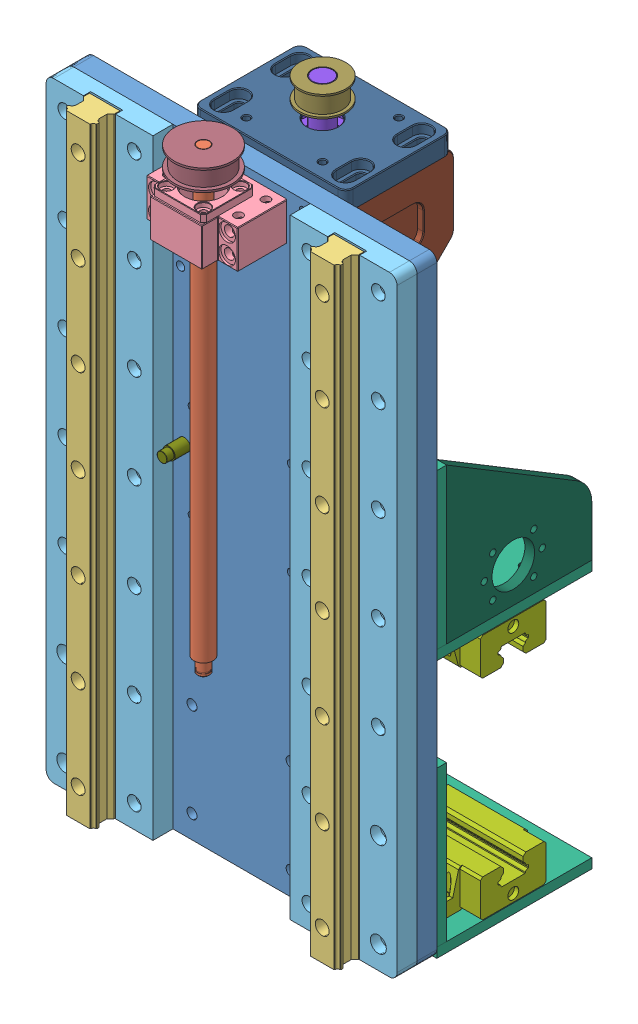
SolidWorks assembly Z Head, configuration Default. Lengths in mm.
Overall size (240 423.59 158.6).
25 component instances, 16 part files, 116 mates.
Components (placement in the parent):
- faceplate-1: faceplate [Default] at origin size (230 400 13)
- ballscrew-1: ballscrew [Z Axis] at (0 73.5865 38) x (-1 0 0) z (0 1 0) size (12.64 12.64 300)
- HGR20-1: HGR20 [400mm] at (80 0 37.15) x (1 0 0) z (0 -1 0) size (20 17.5 400)
- HGR20-2: HGR20 [400mm] at (-80 0 37.15) x (1 0 0) z (0 -1 0) size (20 17.5 400)
- BK12-1: BK12 [Default] at (0 182.35 38) x (-1 0 0) z (0 1 0) size (60 43 30.41)
- rail spacer-1: rail spacer [Right] at (80 0 13) size (70 400 13.1)
- rail spacer-2: rail spacer [Left] at (-80 0 13) x (-1 0 0) z (0 0 1) size (70 400 13.1)
- L bracket-1: L bracket [Bottom] at (0 -196.825 -50.8) size (230 107.95 101.6)
- L bracket-2: L bracket [Top] at (0 -27.905 -50.8) size (230 107.95 101.6)
- HGW20CC-1: HGW20CC [Default] at (76.37 -47.08 -50.1) size (77.26 24.9 63)
- HGW20CC-2: HGW20CC [Default] at (-76.37 -47.08 -50.1) size (77.26 24.9 63)
- HGW20CC-3: HGW20CC [Default] at (76.37 -177.65 -50.1) x (-1 0 0) z (0 0 1) size (77.26 24.9 63)
- HGW20CC-4: HGW20CC [Default] at (-76.37 -177.65 -50.1) x (-1 0 0) z (0 0 1) size (77.26 24.9 63)
- servo JMC_400W_AC_with_brake-1: servo JMC_400W_AC_with_brake [Default] at (0 74.9865 -40.1143) x (0 0 -1) z (1 0 0) size (60 164.6 60)
- nut_XY-1: nut_XY [Default] at (-103 -1.56 -50.1) x (0 0 1) z (-1 0 0) size (48 40 44)
- z motor attach-1: z motor attach [Default] at (0 186.9865 -40.1143) size (100 12.7 70)
- z motor attach supports-1: z motor attach supports [Default] at (40 146.9865 -40) size (12.7 80 80)
- z motor attach supports-2: z motor attach supports [Default] at (-40 146.9865 -40) size (12.7 80 80)
- Pulley motor-1: Pulley motor [Default] at (0 216.5865 -40.1143) x (0.999978 0 -0.006689) z (0.006689 0 0.999978) size (30.2 14 30.2)
- Pulley Z screw-1: Pulley Z screw [Default] at (0 216.5865 38) size (38 14 38)
- Z Spacer-1: Z Spacer [Default] at (-80 0 22.05) x (0 0 -1) z (1 0 0) size (1.2 400 21)
- Z Spacer-2: Z Spacer [Default] at (80 0 22.05) x (0 0 -1) z (-1 0 0) size (1.2 400 21)
- Z_nut_mount-1: Z_nut_mount [Default] at (-115 -24.73 -6.35) x (-1 0 0) z (0 0 -1) size (6.35 101.6 95.25)
- Z_nut_mount-2: Z_nut_mount [Default] at (108.65 -24.73 -6.35) x (-1 0 0) z (0 0 -1) size (6.35 101.6 95.25)
- limit_sensor-1: limit_sensor [Default] at (-37.5 22 27.6577) size (7.92 7.92 51)
Mates (geometry in assembly coordinates):
- Coincident1: coordinate: point of faceplate-1
- Distance1: distance = 12.7 mm anti-aligned: plane of servo JMC_400W_AC-1 through (30 167.3 -12.7) normal (0 0 1); plane of faceplate-1 through (0 0 0) normal (0 0 -1)
- Distance2: distance = 12.7 mm aligned: plane of servo JMC_400W_AC-1 through (0 167.3 -42.7) normal (0 1 0); plane of faceplate-1 through (115 200 13) normal (0 1 0)
- Width1: width aligned: plane of servo JMC_400W_AC-1 through (30 167.3 -72.7) normal (1 0 0); plane of faceplate-1 through (-30 167.3 -72.7) normal (-1 0 0); plane of servo JMC_400W_AC-1 through (115 200 13) normal (1 0 0); plane of faceplate-1 through (-115 200 13) normal (-1 0 0)
- Coincident5: coincident aligned: plane of faceplate-1 through (115 200 13) normal (0 1 0); plane of HGR20-1 through (70.3536 200 34.5036) normal (0 1 0)
- Coincident7: coincident aligned: plane of faceplate-1 through (115 200 13) normal (0 1 0); plane of HGR20-2 through (-89.6464 200 34.5036) normal (0 1 0)
- Coincident8: coincident anti-aligned: plane of faceplate-1 through (0 0 13) normal (0 0 1); plane of BK12-1 through (30 194.85 13) normal (0 0 -1)
- Coincident9: coincident aligned: plane of faceplate-1 through (115 200 13) normal (0 1 0); plane of BK12-1 through (0 200 38) normal (0 1 0)
- Width2: width anti-aligned: plane of BK12-1 through (-30 194.85 45.5) normal (-1 0 0); plane of faceplate-1 through (30 194.85 45.5) normal (1 0 0); plane of BK12-1 through (115 200 13) normal (1 0 0); plane of faceplate-1 through (-115 200 13) normal (-1 0 0)
- Concentric1: concentric aligned: cylinder of ballscrew-1 through (0 223.5865 38) axis (0 1 0) radius 4; cylinder of BK12-1 through (0 182.35 38) axis (0 1 0) radius 6
- Coincident10: coincident anti-aligned: plane of ballscrew-1 through (0 169.5865 42.94) normal (0 1 0); plane of BK12-1 through (6 169.5865 38) normal (0 -1 0)
- Coincident14: coincident aligned: plane of HGR20-1 through (72.35 -200 40.15) normal (0 0 1); plane of HGR20-2 through (-87.65 -200 40.15) normal (0 0 1)
- Coincident15: coincident aligned: plane of faceplate-1 through (115 200 13) normal (0 1 0); plane of rail spacer-1 through (115 200 21.45) normal (0 1 0)
- Coincident16: coincident aligned: plane of faceplate-1 through (115 200 13) normal (1 0 0); plane of rail spacer-1 through (115 200 21.45) normal (1 0 0)
- Coincident17: coincident anti-aligned: plane of faceplate-1 through (0 0 13) normal (0 0 1); plane of rail spacer-1 through (80 0 13) normal (0 0 -1)
- Coincident18: coincident anti-aligned: plane of faceplate-1 through (0 0 13) normal (0 0 1); plane of rail spacer-2 through (-80 0 13) normal (0 0 -1)
- Coincident22: coincident aligned: plane of faceplate-1 through (115 -200 13) normal (0 -1 0); plane of L bracket-1 through (115 -200 0) normal (0 -1 0)
- Coincident23: coincident anti-aligned: plane of faceplate-1 through (0 0 0) normal (0 0 -1); plane of L bracket-1 through (115 -200 0) normal (0 0 1)
- Coincident24: coincident aligned: plane of faceplate-1 through (115 200 13) normal (1 0 0); plane of L bracket-1 through (115 -196.825 -50.8) normal (1 0 0)
- Coincident28: coincident aligned: plane of HGW20CC-1 through (155.153 -40.4358 -81.6) normal (0 0 -1); plane of HGW20CC-2 through (2.413 -40.4358 -81.6) normal (0 0 -1)
- Coincident29: coincident aligned: plane of HGW20CC-1 through (155.153 -31.08 -44.745) normal (0 1 0); plane of HGW20CC-2 through (2.413 -31.08 -44.745) normal (0 1 0)
- Coincident31: coincident anti-aligned: plane of L bracket-1 through (115 -193.65 -6.35) normal (0 1 0); plane of HGW20CC-4 through (-155.153 -193.65 -44.745) normal (0 -1 0)
- Coincident32: coincident anti-aligned: plane of L bracket-1 through (115 -193.65 -6.35) normal (0 1 0); plane of HGW20CC-3 through (-2.413 -193.65 -44.745) normal (0 -1 0)
- Coincident33: coincident aligned: plane of HGW20CC-3 through (37.74 -170.22 -71.69) normal (0 0 -1); plane of HGW20CC-4 through (-115 -170.22 -71.69) normal (0 0 -1)
- Coincident34: coincident aligned: plane of L bracket-1 through (115 -196.825 -50.8) normal (1 0 0); plane of HGW20CC-3 through (115 -180.3114 -40.4536) normal (1 0 0)
- Distance6: distance = 45 mm anti-aligned: plane of HGW20CC-3 through (37.74 -173.485 -56.6) normal (0 0 1); plane of L bracket-1 through (115 -200 -101.6) normal (0 0 -1)
- Coincident37: coincident aligned: plane of HGW20CC-1 through (155.153 -40.4358 -81.6) normal (0 0 -1); plane of HGW20CC-3 through (-2.413 -184.2942 -81.6) normal (0 0 -1)
- Coincident41: coincident aligned: plane of L bracket-1 through (-115 -196.825 -50.8) normal (-1 0 0); plane of HGW20CC-4 through (-115 -180.3114 -40.4536) normal (-1 0 0)
- Width5: width aligned: plane of SFU1610 nut housing-1 through (-20 -21.56 -24.1) normal (0 0 1); plane of HGW20CC-2 through (-20 -21.56 -76.1) normal (0 0 -1); plane of SFU1610 nut housing-1 through (2.413 -40.4358 -18.6) normal (0 0 1); plane of HGW20CC-2 through (2.413 -40.4358 -81.6) normal (0 0 -1)
- Concentric2: concentric anti-aligned: cylinder of SFU1610 nut housing-1 through (-20 -1.56 -50.1) axis (1 0 0) radius 14; cylinder of nut_XY-1 through (-120.9283 -1.56 -50.1) axis (-1 0 0) radius 14
- Coincident46: coincident anti-aligned: plane of SFU1610 nut housing-1 through (-20 -1.56 -50.1) normal (-1 0 0); plane of nut_XY-1 through (-115 22.44 -50.1) normal (1 0 0)
- Coincident47: coincident aligned: plane of SFU1610 nut housing-1 through (-20 18.44 -64.1) normal (0 1 0); plane of nut_XY-1 through (-81 18.44 -30.1) normal (0 1 0)
- Coincident51: coincident aligned: plane of faceplate-1 through (-115 200 13) normal (-1 0 0); plane of rail spacer-2 through (-115 -200 21.45) normal (-1 0 0)
- Coincident52: coincident aligned: plane of faceplate-1 through (115 200 13) normal (0 1 0); plane of rail spacer-2 through (-115 200 21.45) normal (0 1 0)
- Concentric3: concentric anti-aligned: cylinder of servo JMC_400W_AC_with_brake-1 through (0 269.9855 -40.1143) axis (0 -1 0) radius 7; cylinder of pulley 5М-20T-1 through (0 201.9116 -30) axis (0 1 0) radius 6
- Concentric4: concentric anti-aligned: cylinder of ballscrew-1 through (0 223.5865 38) axis (0 1 0) radius 4; cylinder of pulley 5М-20T-2 through (0 201.9951 37) axis (0 -1 0) radius 6
- Concentric5: concentric aligned: cylinder of servo JMC_400W_AC_with_brake-1 through (0 269.9855 -40.1143) axis (0 -1 0) radius 7; cylinder of z motor attach-1 through (0 199.6865 -40.1143) axis (0 -1 0) radius 10
- Coincident56: coincident anti-aligned: plane of servo JMC_400W_AC_with_brake-1 through (0 193.9865 -40.1143) normal (0 1 0); plane of z motor attach-1 through (0 193.9865 -40.1143) normal (0 -1 0)
- Coincident59: coincident aligned: plane of ballscrew-1 through (0 223.5865 38) normal (0 1 0); plane of servo JMC_400W_AC_with_brake-1 through (0 223.5865 -40.1143) normal (0 1 0)
- Concentric6: concentric aligned: cylinder of ballscrew-1 through (0 223.5865 38) axis (0 1 0) radius 4; cylinder of 5m pulley 20T-1 through (0 205.4115 37) axis (0 1 0) radius 4
- Concentric7: concentric anti-aligned: cylinder of servo JMC_400W_AC_with_brake-1 through (0 269.9855 -40.1143) axis (0 -1 0) radius 7; cylinder of 5m pulley 20T-2 through (0 205.4115 -40.3837) axis (0 1 0) radius 4
- Coincident60: coincident aligned: plane of servo JMC_400W_AC_with_brake-1 through (0 223.5865 -40.1143) normal (0 1 0); plane of 5m pulley 20T-2 through (0 223.5865 -40.3837) normal (0 1 0)
- Coincident61: coincident aligned: plane of ballscrew-1 through (0 223.5865 38) normal (0 1 0); plane of 5m pulley 20T-1 through (0 223.5865 37) normal (0 1 0)
- Width6: width anti-aligned: plane of faceplate-1 through (115 200 13) normal (1 0 0); plane of faceplate-1 through (-115 200 13) normal (-1 0 0); plane of z motor attach-1 through (-50 199.6865 -5.1143) normal (-1 0 0); plane of z motor attach-1 through (50 199.6865 -5.1143) normal (1 0 0)
- Coincident62: coincident anti-aligned: plane of faceplate-1 through (0 0 0) normal (0 0 -1); plane of z motor attach supports-1 through (46.35 106.9865 0) normal (0 0 1)
- Coincident63: coincident anti-aligned: plane of z motor attach-1 through (0 186.9865 -40.1143) normal (0 -1 0); plane of z motor attach supports-1 through (46.35 186.9865 -80) normal (0 1 0)
- Parallel3: parallel aligned: plane of faceplate-1 through (0 0 13) normal (0 0 1); plane of ballscrew-1 through (0 73.5865 38) normal (0 0 1)
- Width7: width anti-aligned: plane of z motor attach supports-1 through (33.65 146.9865 -40) normal (-1 0 0); plane of z motor attach supports-1 through (46.35 146.9865 -40) normal (1 0 0); plane of z motor attach-1 through (36.8 186.9865 -65.1143) normal (1 0 0); plane of z motor attach-1 through (43.2 186.9865 -65.1143) normal (-1 0 0)
- Coincident65: coincident anti-aligned: plane of faceplate-1 through (0 0 0) normal (0 0 -1); plane of z motor attach supports-2 through (-33.65 106.9865 0) normal (0 0 1)
- Coincident66: coincident anti-aligned: plane of z motor attach-1 through (0 186.9865 -40.1143) normal (0 -1 0); plane of z motor attach supports-2 through (-33.65 186.9865 -80) normal (0 1 0)
- Width8: width anti-aligned: plane of z motor attach supports-2 through (-33.65 146.9865 -40) normal (1 0 0); plane of z motor attach supports-2 through (-46.35 146.9865 -40) normal (-1 0 0); plane of z motor attach-1 through (-36.8 186.9865 -65.1143) normal (-1 0 0); plane of z motor attach-1 through (-43.2 186.9865 -65.1143) normal (1 0 0)
- Concentric8: concentric anti-aligned: cylinder of servo JMC_400W_AC_with_brake-1 through (0 269.9855 -40.1143) axis (0 -1 0) radius 7; cylinder of GPA48GT3090-A-H14.stp-1 through (0 209.5865 -57.1358) axis (0 1 0) radius 7
- Coincident67: coincident aligned: plane of servo JMC_400W_AC_with_brake-1 through (0 223.5865 -40.1143) normal (0 1 0); plane of GPA48GT3090-A-H14.stp-1 through (0 223.5865 -57.1358) normal (0 1 0)
- Concentric9: concentric anti-aligned: cylinder of servo JMC_400W_AC_with_brake-1 through (0 269.9855 -40.1143) axis (0 -1 0) radius 7; cylinder of GPM36GT3060-B-H14.stp-1 through (0 204.5865 -57.1358) axis (0 1 0) radius 7
- Coincident68: coincident aligned: plane of servo JMC_400W_AC_with_brake-1 through (0 223.5865 -40.1143) normal (0 1 0); plane of GPM36GT3060-B-H14.stp-1 through (0 223.5865 -57.1358) normal (0 1 0)
- Concentric10: concentric aligned: cylinder of ballscrew-1 through (0 223.5865 38) axis (0 1 0) radius 4; cylinder of GPA36GT3090-B-P8.stp-1 through (0 208.5865 37) axis (0 1 0) radius 4
- Coincident69: coincident anti-aligned: plane of ballscrew-1 through (0 208.5865 42) normal (0 1 0); plane of GPA36GT3090-B-P8.stp-1 through (10.046 208.5865 43.5633) normal (0 -1 0)
- Concentric11: concentric anti-aligned: cylinder of servo JMC_400W_AC_with_brake-1 through (0 269.9855 -40.1143) axis (0 -1 0) radius 7; cylinder of GPA36GT3090-B-P14.stp-1 through (0 201.5865 -57.1358) axis (0 1 0) radius 7
- Coincident70: coincident aligned: plane of servo JMC_400W_AC_with_brake-1 through (0 223.5865 -40.1143) normal (0 1 0); plane of GPA36GT3090-B-P14.stp-1 through (0 223.5865 -57.1358) normal (0 1 0)
- Concentric12: concentric anti-aligned: cylinder of ballscrew-1 through (0 223.5865 38) axis (0 1 0) radius 4; cylinder of GPA36GT3090-A-P8.stp-1 through (0 223.5865 37) axis (0 -1 0) radius 4
- Coincident71: coincident aligned: plane of ballscrew-1 through (0 223.5865 38) normal (0 1 0); plane of GPA36GT3090-A-P8.stp-1 through (-11.1648 223.5865 46.2519) normal (0 1 0)
- Concentric13: concentric anti-aligned: cylinder of servo JMC_400W_AC_with_brake-1 through (0 269.9855 -40.1143) axis (0 -1 0) radius 7; cylinder of GPA48GT3090-A-H14.stp-2 through (0 209.5865 -59.1194) axis (0 1 0) radius 7
- Coincident72: coincident aligned: plane of servo JMC_400W_AC_with_brake-1 through (0 223.5865 -40.1143) normal (0 1 0); plane of GPA48GT3090-A-H14.stp-2 through (0 223.5865 -59.1194) normal (0 1 0)
- Width11: width anti-aligned: plane of HGR20-1 through (90 -200 26.5) normal (1 0 0); plane of rail spacer-1 through (70 -200 26.5) normal (-1 0 0); plane of HGR20-1 through (90.5 0 26.1) normal (-1 0 0); plane of rail spacer-1 through (69.5 0 26.1) normal (1 0 0)
- Width12: width anti-aligned: plane of HGR20-2 through (-90 -200 26.5) normal (-1 0 0); plane of rail spacer-2 through (-70 -200 26.5) normal (1 0 0); plane of HGR20-2 through (-90.5 0 26.1) normal (1 0 0); plane of rail spacer-2 through (-69.5 0 26.1) normal (-1 0 0)
- Parallel5: parallel aligned: plane of servo JMC_400W_AC_with_brake-1 through (-30 193.9865 -70.1143) normal (-1 0 0); plane of z motor attach supports-2 through (-46.35 146.9865 -40) normal (-1 0 0)
- Coincident86: coincident anti-aligned: plane of faceplate-1 through (0 0 0) normal (0 0 -1); plane of L bracket-2 through (115 -31.08 0) normal (0 0 1)
- Coincident87: coincident anti-aligned: plane of L bracket-2 through (115 -31.08 0) normal (0 -1 0); plane of HGW20CC-1 through (155.153 -31.08 -44.745) normal (0 1 0)
- Coincident88: coincident aligned: plane of faceplate-1 through (115 200 13) normal (1 0 0); plane of L bracket-2 through (115 -27.905 -50.8) normal (1 0 0)
- Distance9: distance = 136.6 mm anti-aligned: plane of HGW20CC-3 through (37.74 -180.665 -50.1) normal (0 1 0); plane of HGW20CC-1 through (115 -44.065 -50.1) normal (0 -1 0)
- Coincident94: coincident aligned: plane of L bracket-2 through (-115 -27.905 -50.8) normal (-1 0 0); plane of HGW20CC-2 through (-115 -44.4186 -40.4536) normal (-1 0 0)
- Coincident95: coincident aligned: plane of L bracket-2 through (115 -27.905 -50.8) normal (1 0 0); plane of HGW20CC-1 through (115 -44.4186 -40.4536) normal (1 0 0)
- Distance10: distance = 3.17 mm anti-aligned: plane of SFU1610 nut housing-1 through (-20 -21.56 -76.1) normal (0 -1 0); plane of L bracket-2 through (115 -24.73 -6.35) normal (0 1 0)
- Width13: width anti-aligned: plane of L bracket-2 through (-115 -27.905 -50.8) normal (-1 0 0); plane of SFU1610 nut housing-1 through (115 -27.905 -50.8) normal (1 0 0); plane of L bracket-2 through (20 -1.56 -50.1) normal (1 0 0); plane of SFU1610 nut housing-1 through (-20 -1.56 -50.1) normal (-1 0 0)
- Concentric18: concentric aligned: cylinder of L bracket-2 through (-32.5 -16.08 0) axis (0 0 -1) radius 3.3; cylinder of socket head cap screw_am-19 through (-32.5 -16.08 -44.1) axis (0 0 -1) radius 5
- Coincident102: coincident anti-aligned: plane of L bracket-2 through (115 -24.73 -6.35) normal (0 0 -1); plane of socket head cap screw_am-19 through (-32.5 -11.08 -6.35) normal (0 0 1)
- Concentric19: concentric aligned: cylinder of L bracket-2 through (-32.5 45.5867 0) axis (0 0 -1) radius 3.3; cylinder of socket head cap screw_am-20 through (-32.5 45.5867 -44.1) axis (0 0 -1) radius 5
- Coincident103: coincident anti-aligned: plane of L bracket-2 through (115 -24.73 -6.35) normal (0 0 -1); plane of socket head cap screw_am-20 through (-32.5 50.5867 -6.35) normal (0 0 1)
- Concentric20: concentric aligned: cylinder of L bracket-2 through (32.5 -16.08 0) axis (0 0 -1) radius 3.3; cylinder of socket head cap screw_am-21 through (32.5 -16.08 -44.1) axis (0 0 -1) radius 5
- Coincident104: coincident anti-aligned: plane of L bracket-2 through (115 -24.73 -6.35) normal (0 0 -1); plane of socket head cap screw_am-21 through (32.5 -11.08 -6.35) normal (0 0 1)
- Concentric21: concentric aligned: cylinder of L bracket-2 through (32.5 45.5867 0) axis (0 0 -1) radius 3.3; cylinder of socket head cap screw_am-22 through (32.5 45.5867 -44.1) axis (0 0 -1) radius 5
- Coincident105: coincident anti-aligned: plane of L bracket-2 through (115 -24.73 -6.35) normal (0 0 -1); plane of socket head cap screw_am-22 through (32.5 50.5867 -6.35) normal (0 0 1)
- Concentric22: concentric aligned: cylinder of L bracket-2 through (102.75 45.5867 0) axis (0 0 -1) radius 3.3; cylinder of socket head cap screw_am-23 through (102.75 45.5867 -44.1) axis (0 0 -1) radius 5
- Coincident106: coincident anti-aligned: plane of L bracket-2 through (115 -24.73 -6.35) normal (0 0 -1); plane of socket head cap screw_am-23 through (102.75 50.5867 -6.35) normal (0 0 1)
- Concentric23: concentric aligned: cylinder of L bracket-2 through (102.75 -16.08 0) axis (0 0 -1) radius 3.3; cylinder of socket head cap screw_am-24 through (102.75 -16.08 -44.1) axis (0 0 -1) radius 5
- Coincident107: coincident anti-aligned: plane of L bracket-2 through (115 -24.73 -6.35) normal (0 0 -1); plane of socket head cap screw_am-24 through (102.75 -11.08 -6.35) normal (0 0 1)
- Concentric24: concentric aligned: cylinder of L bracket-2 through (-102.75 45.5867 0) axis (0 0 -1) radius 3.3; cylinder of socket head cap screw_am-25 through (-102.75 45.5867 -44.1) axis (0 0 -1) radius 5
- Coincident108: coincident anti-aligned: plane of L bracket-2 through (115 -24.73 -6.35) normal (0 0 -1); plane of socket head cap screw_am-25 through (-102.75 50.5867 -6.35) normal (0 0 1)
- Concentric25: concentric aligned: cylinder of L bracket-2 through (-102.75 -16.08 0) axis (0 0 -1) radius 3.3; cylinder of socket head cap screw_am-26 through (-102.75 -16.08 -44.1) axis (0 0 -1) radius 5
- Coincident109: coincident anti-aligned: plane of L bracket-2 through (115 -24.73 -6.35) normal (0 0 -1); plane of socket head cap screw_am-26 through (-102.75 -11.08 -6.35) normal (0 0 1)
- Concentric26: concentric anti-aligned: cylinder of servo JMC_400W_AC_with_brake-1 through (0 269.9855 -40.1143) axis (0 -1 0) radius 7; cylinder of Pulley motor-1 through (0 224.2865 -40.1143) axis (0 1 0) radius 7
- Coincident110: coincident aligned: plane of servo JMC_400W_AC_with_brake-1 through (0 223.5865 -40.1143) normal (0 1 0); plane of Pulley motor-1 through (0.0468 223.5865 -33.1145) normal (0 1 0)
- Concentric27: concentric aligned: cylinder of ballscrew-1 through (0 223.5865 38) axis (0 1 0) radius 4; cylinder of Pulley Z screw-1 through (0 224.2865 38) axis (0 1 0) radius 4
- Coincident111: coincident aligned: plane of ballscrew-1 through (0 223.5865 38) normal (0 1 0); plane of Pulley Z screw-1 through (0 223.5865 42) normal (0 1 0)
- ProfileCenter1: profile center anti-aligned: plane of rail spacer-1 through (80 0 21.45) normal (0 0 1); plane of Z Spacer-2 through (80 0 21.45) normal (0 0 -1)
- ProfileCenter2: profile center anti-aligned: plane of rail spacer-2 through (-80 0 21.45) normal (0 0 1); plane of Z Spacer-1 through (-80 0 21.45) normal (0 0 -1)
- Coincident115: coincident anti-aligned: plane of HGR20-1 through (70 -200 22.65) normal (0 0 -1); plane of Z Spacer-2 through (80 0 22.65) normal (0 0 1)
- Width14: width anti-aligned: plane of Z cover-1 through (-116.3 233.5865 70) normal (1 0 0); plane of Z cover-1 through (116.3 233.5865 70) normal (-1 0 0); plane of faceplate-1 through (-115 200 13) normal (-1 0 0); plane of faceplate-1 through (115 200 13) normal (1 0 0)
- Coincident116: coincident aligned: plane of faceplate-1 through (0 0 0) normal (0 0 -1); plane of Z cover-1 through (116.3 234.7865 0) normal (0 0 -1)
- Distance11: distance = 10 mm anti-aligned: plane of servo JMC_400W_AC_with_brake-1 through (0 223.5865 -40.1143) normal (0 1 0); plane of Z cover-1 through (0 233.5865 70) normal (0 -1 0)
- Coincident117: coincident anti-aligned: plane of L bracket-2 through (115 -24.73 -6.35) normal (0 0 -1); plane of Z_nut_mount-1 through (-108.65 76.87 -6.35) normal (0 0 1)
- Coincident118: coincident aligned: plane of L bracket-2 through (-115 -27.905 -50.8) normal (-1 0 0); plane of Z_nut_mount-1 through (-115 -24.73 -6.35) normal (-1 0 0)
- Coincident119: coincident anti-aligned: plane of L bracket-2 through (115 -24.73 -6.35) normal (0 1 0); plane of Z_nut_mount-1 through (-108.65 -24.73 -6.35) normal (0 -1 0)
- Coincident123: coincident anti-aligned: plane of L bracket-2 through (115 -24.73 -6.35) normal (0 0 -1); plane of Z_nut_mount-2 through (115 76.87 -6.35) normal (0 0 1)
- Coincident124: coincident aligned: plane of L bracket-2 through (115 -27.905 -50.8) normal (1 0 0); plane of Z_nut_mount-2 through (115 -24.73 -6.35) normal (1 0 0)
- Coincident125: coincident anti-aligned: plane of L bracket-2 through (115 -24.73 -6.35) normal (0 1 0); plane of Z_nut_mount-2 through (115 -24.73 -6.35) normal (0 -1 0)
- Concentric28: concentric aligned: cylinder of nut_XY-1 through (-120.9283 -1.56 -50.1) axis (-1 0 0) radius 14; cylinder of Z_nut_mount-1 through (-108.65 -1.56 -50.1) axis (-1 0 0) radius 14
- Coincident127: coincident anti-aligned: plane of nut_XY-1 through (-115 22.44 -50.1) normal (1 0 0); plane of Z_nut_mount-1 through (-115 -24.73 -6.35) normal (-1 0 0)
- Parallel6: parallel aligned: plane of L bracket-2 through (115 -31.08 0) normal (0 -1 0); plane of nut_XY-1 through (-81 -21.56 -30.1) normal (0 -1 0)
- Concentric29: concentric anti-aligned: cylinder of faceplate-1 through (-37.5 22 53.5) axis (0 0 -1) radius 4; cylinder of limit_sensor-1 through (-37.5 22 50.2492) axis (0 0 1) radius 3.96
- Concentric31: concentric anti-aligned: cylinder of faceplate-1 through (-40 193.65 13) axis (0 0 -1) radius 2.1; cylinder of socket head cap screw_am-28 through (-40 193.65 54.2143) axis (0 0 1) radius 3.5
- Concentric32: concentric anti-aligned: cylinder of faceplate-1 through (40 193.65 13) axis (0 0 -1) radius 2.1; cylinder of socket head cap screw_am-29 through (40 193.65 54.2143) axis (0 0 1) radius 3.5
- Coincident131: coincident anti-aligned: plane of z motor attach-1 through (50 199.6865 -5.1143) normal (0 0 1); plane of socket head cap screw_am-28 through (-38.8928 194.8189 -1.5357) normal (0 0 -1)
- Coincident132: coincident anti-aligned: plane of z motor attach-1 through (50 199.6865 -5.1143) normal (0 0 1); plane of socket head cap screw_am-29 through (41.6082 193.7262 -1.5357) normal (0 0 -1)
- Distance12: distance = 5.1143 mm anti-aligned: plane of z motor attach-1 through (50 199.6865 -5.1143) normal (0 0 1); plane of faceplate-1 through (0 0 0) normal (0 0 -1)
- Distance13: distance = 1.5577 mm aligned: plane of limit_sensor-1 through (-37.5 22 27.6577) normal (0 0 1); plane of rail spacer-2 through (-80 0 26.1) normal (0 0 1)
